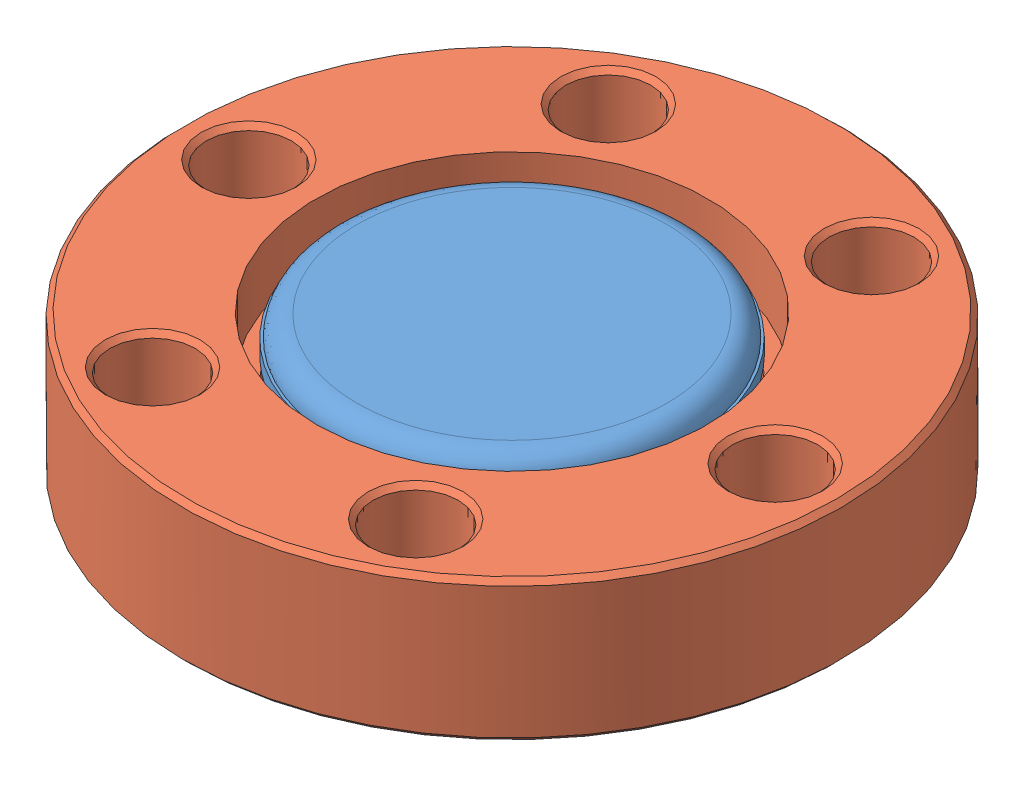
SolidWorks assembly window 133 SW, configuration Default. Lengths in mm.
Overall size (33.78 7.24 33.78).
2 component instances, 2 part files, 0 mates.
Components (placement in the parent):
- 045000-1: 045000 [Default] at (0 7.1374 0) size (18.29 4.7 18.29)
- 945010-1: 945010 [Default] at origin size (33.78 7.24 33.78)
